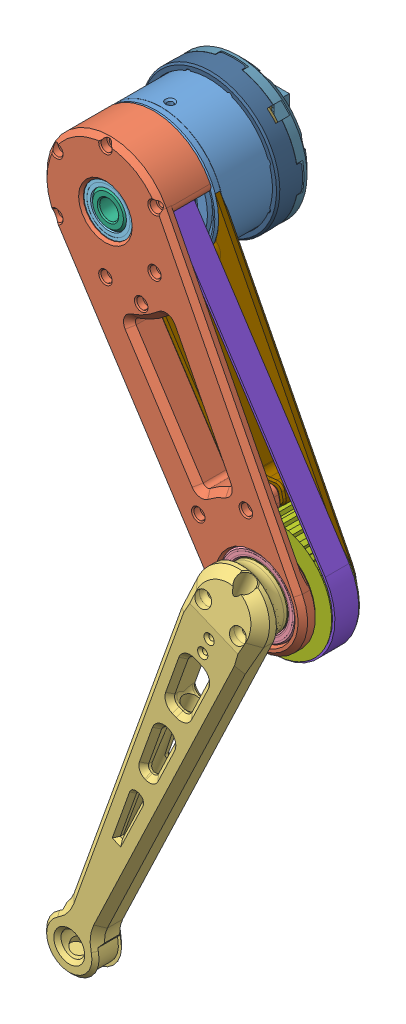
SolidWorks assembly Leg 010, configuration Default. Lengths in mm.
Overall size (133.1 311.2 88.94).
16 component instances, 15 part files, 37 mates.
Components (placement in the parent):
- Servo 010-1: Servo 010 [Default] at (15.0435 28.5731 29.2983) size (52.8 52.8 26)
- Femur 011-1: Femur 011 [Default] at (15.0435 28.5731 74.4483) x (0.866025 0.5 0) z (0 0 1) size (53 172 20.25)
- Low Limb 020-1: Low Limb 020 [Predeterminado] at (77.7935 -80.1131 89.8983) x (-0.92322 0.384271 0) z (0 0 -1) size (30 188.77 21.4)
- 6705 Bearing-1: 6705 Bearing [Predeterminado] at (77.7935 -80.1131 71.4983) x (0.989844 0.142156 0) z (0.142156 -0.989844 0) size (32 4.1 32)
- Bearing 15x24x5mm-1: Bearing 15x24x5mm [Predeterminado] at (15.0435 28.5731 70.6483) x (1 0 0) z (0 -1 0) size (24 5.1 24)
- Pulley A 36T 011-1: Pulley A 36T 011 [Predeterminado] at (15.0435 28.5731 66.0983) x (-0.95639 -0.292092 0) z (0 0 -1) size (36.31 36.31 18.05)
- Pulley B 36T 010-2: Pulley B 36T 010 [Predeterminado] at (77.7935 -80.1131 55.8983) x (0.384271 0.92322 0) z (0 0 1) size (49.11 49.11 20.55)
- Belt 380mm 010-1: Belt 380mm 010 [Default] at (77.7935 -80.1131 65.9983) x (-0.5 0.866025 0) z (-0.866025 -0.5 0) size (168.7 10 50)
- Femur B 011-1: Femur B 011 [Default] at (15.0435 28.5731 49.7229) x (-0.866025 -0.5 0) z (0 0 -1) size (52.55 140.48 13)
- 6705 Bearing-2: 6705 Bearing [Predeterminado] at (77.7935 -80.1131 52.4229) x (0.58942 -0.807827 0) z (-0.807827 -0.58942 0) size (32 4.1 32)
- Back Plate 011-1: Back Plate 011 [Default] at (15.0435 28.5731 31.0483) x (1 0 0) z (0 1 0) size (58 10.25 57.37)
- Pulley B Plate 010-1: Pulley B Plate 010 [Default] at (77.7935 -80.1131 48.8983) x (-0.384271 -0.92322 0) z (0 0 -1) size (27 27 7.25)
- Dagor Controller Board 2.5-1: Dagor Controller Board 2.5 [Predeterminado] at (15.0435 28.5731 24.4983) size (44 44 7.5)
- ESP32-WROOM-32U-1: ESP32-WROOM-32U [Default] at (9.0435 43.9731 23.5333) x (1 0 0) z (0 0 -1) size (18.07 19.38 3.04)
- Back Plate B 011-1: Back Plate B 011 [Default] at (15.0435 28.5731 22.7073) x (-1 0 0) z (0 0 -1) size (58 58 21.75)
- Magnet Holder 010-1: Magnet Holder 010 [Default] at (15.0435 28.5731 36.0983) x (1 0 0) z (0 0 -1) size (9 9 8.5)
Mates (geometry in assembly coordinates):
- Concentric1: concentric anti-aligned: cylinder of Servo 010-1 through (15.0435 28.5731 54.1983) axis (0 0 -1) radius 26.4; cylinder of Femur 011-1 through (15.0435 28.5731 70.4483) axis (0 0 1) radius 26.5
- Coincident1: coincident anti-aligned: plane of Servo 010-1 through (15.0435 28.5731 54.1983) normal (0 0 1); plane of Femur 011-1 through (15.0435 28.5731 54.1983) normal (0 0 -1)
- Concentric2: concentric aligned: cylinder of Servo 010-1 through (35.6116 40.4481 49.0983) axis (0 0 1) radius 1.25; cylinder of Femur 011-1 through (35.6116 40.4481 70.4483) axis (0 0 1) radius 1.4
- Concentric3: concentric aligned: cylinder of Femur 011-1 through (77.7935 -80.1131 70.4483) axis (0 0 1) radius 14.25; cylinder of Low Limb 020-1 through (77.7935 -80.1131 73.4983) axis (0 0 1) radius 12.5
- Coincident3: coincident anti-aligned: plane of Low Limb 020-1 through (77.7935 -80.1131 73.4983) normal (0 0 -1); plane of 6705 Bearing-1 through (77.7935 -80.1131 73.4983) normal (0 0 1)
- Concentric5: concentric aligned: cylinder of Femur 011-1 through (15.0435 28.5731 73.1983) axis (0 0 -1) radius 12.2; cylinder of Bearing 15x24x5mm-1 through (15.0435 28.5731 73.1483) axis (0 0 -1) radius 12
- Coincident4: coincident anti-aligned: plane of Femur 011-1 through (15.0435 28.5731 73.1983) normal (0 0 -1); plane of Bearing 15x24x5mm-1 through (15.0435 28.5731 73.1983) normal (0 0 1)
- Concentric7: concentric aligned: cylinder of 6705 Bearing-1 through (77.7935 -80.1131 73.4983) axis (0 0 -1) radius 12.5; cylinder of Pulley B 36T 010-2 through (77.7935 -80.1131 72.1983) axis (0 0 -1) radius 12.45
- Concentric8: concentric aligned: cylinder of Bearing 15x24x5mm-1 through (15.0435 28.5731 73.1483) axis (0 0 -1) radius 7.5; cylinder of Pulley A 36T 010-1 through (15.0435 28.5731 73.3483) axis (0 0 -1) radius 7.45
- Coincident7: coincident anti-aligned: plane of Servo 010-1 through (15.0435 28.5731 55.2983) normal (0 0 1); plane of Pulley A 36T 010-1 through (15.0435 28.5731 55.2983) normal (0 0 -1)
- Parallel1: parallel anti-aligned: plane of Low Limb 020-1 through (85.4795 -73.6179 68.4983) normal (0.92322 -0.384271 0); plane of Pulley B 36T 010-2 through (85.5449 -73.5909 63.1983) normal (-0.92322 0.384271 0)
- Concentric9: concentric aligned: cylinder of Pulley A 36T 010-1 through (15.0435 28.5731 55.8983) axis (0 0 1) radius 17.4; cylinder of Belt 380mm 010-1 through (15.0435 28.5731 55.9983) axis (0 0 1) radius 17.2
- Concentric10: concentric anti-aligned: cylinder of Pulley B 36T 010-2 through (77.7935 -80.1131 66.0983) axis (0 0 -1) radius 24; cylinder of Belt 380mm 010-1 through (77.7935 -80.1131 55.9983) axis (0 0 1) radius 24
- Width1: width anti-aligned: plane of Pulley A 36T 011-1 through (15.0435 28.5731 66.0983) normal (0 0 -1); plane of Belt 380mm 010-1 through (15.0435 28.5731 55.8983) normal (0 0 1); plane of Pulley A 36T 011-1 through (77.7935 -80.1131 65.9983) normal (0 0 1); plane of Belt 380mm 010-1 through (77.7935 -80.1131 55.9983) normal (0 0 -1)
- Concentric14: concentric anti-aligned: cylinder of Servo 010-1 through (15.0435 28.5731 54.1983) axis (0 0 -1) radius 26.4; cylinder of Femur B 010-1 through (15.0435 28.5731 43.7229) axis (0 0 1) radius 26.75
- Concentric15: concentric aligned: cylinder of Femur B 010-1 through (77.7935 -80.1131 54.4729) axis (0 0 -1) radius 16.25; cylinder of 6705 Bearing-2 through (77.7935 -80.1131 54.4229) axis (0 0 -1) radius 16
- Coincident10: coincident anti-aligned: plane of Femur B 010-1 through (77.7935 -80.1131 54.4729) normal (0 0 -1); plane of 6705 Bearing-2 through (77.7935 -80.1131 54.4729) normal (0 0 1)
- Concentric16: concentric anti-aligned: cylinder of Pulley B 36T 010-2 through (77.7935 -80.1131 51.6483) axis (0 0 1) radius 12.45; cylinder of 6705 Bearing-2 through (77.7935 -80.1131 54.4229) axis (0 0 -1) radius 12.5
- Concentric17: concentric anti-aligned: cylinder of Femur 011-1 through (77.7935 -80.1131 69.4483) axis (0 0 1) radius 16.25; cylinder of 6705 Bearing-1 through (77.7935 -80.1131 73.4983) axis (0 0 -1) radius 16
- Coincident11: coincident anti-aligned: plane of Femur 011-1 through (77.7935 -80.1131 69.4483) normal (0 0 1); plane of 6705 Bearing-1 through (77.7935 -80.1131 69.4483) normal (0 0 -1)
- Width2: width anti-aligned: plane of Belt 380mm 010-1 through (77.7935 -80.1131 65.9983) normal (0 0 1); plane of Pulley B 36T 010-2 through (77.7935 -80.1131 55.9983) normal (0 0 -1); plane of Belt 380mm 010-1 through (77.7935 -80.1131 66.0983) normal (0 0 -1); plane of Pulley B 36T 010-2 through (77.7935 -80.1131 55.8983) normal (0 0 1)
- Concentric18: concentric anti-aligned: cylinder of Servo 010-1 through (15.0435 28.5731 31.3983) axis (0 0 -1) radius 9; cylinder of Back Plate 010-1 through (15.0435 28.5731 29.2983) axis (0 0 1) radius 8.75
- Concentric19: concentric anti-aligned: cylinder of Servo 010-1 through (9.0435 28.5731 33.5983) axis (0 0 -1) radius 1.25; cylinder of Back Plate 010-1 through (9.0435 28.5731 29.2983) axis (0 0 1) radius 1.25
- Coincident13: coincident anti-aligned: plane of Pulley B 36T 010-2 through (77.7935 -80.1131 51.6483) normal (0 0 -1); plane of Pulley B Plate 010-1 through (77.7935 -80.1131 51.6483) normal (0 0 1)
- Concentric20: concentric aligned: cylinder of 6705 Bearing-2 through (77.7935 -80.1131 54.4229) axis (0 0 -1) radius 12.5; cylinder of Pulley B Plate 010-1 through (77.7935 -80.1131 51.6483) axis (0 0 -1) radius 12.45
- Concentric21: concentric aligned: cylinder of Pulley B 36T 010-2 through (74.9641 -86.9107 56.6483) axis (0 0 -1) radius 1.45; cylinder of Pulley B Plate 010-1 through (74.9641 -86.9107 51.6483) axis (0 0 -1) radius 1.7
- Coincident14: coincident anti-aligned: plane of Back Plate 010-1 through (15.0435 28.5731 25.2983) normal (0 0 -1); plane of Dagor Controller Board 2.5-1 through (2.5345 41.0821 25.2983) normal (0 0 1)
- Coincident15: coincident anti-aligned: plane of Servo 010-1 through (15.0435 28.5731 29.2983) normal (0 0 -1); plane of Back Plate 010-1 through (15.0435 28.5731 29.2983) normal (0 0 1)
- Concentric23: concentric aligned: cylinder of Back Plate 010-1 through (-3.9565 46.0731 22.7983) axis (0 0 1) radius 1.2; cylinder of Dagor Controller Board 2.5-1 through (-3.9565 46.0731 23.6983) axis (0 0 1) radius 1.5
- Concentric24: concentric aligned: cylinder of Back Plate 010-1 through (34.0435 11.0731 22.7983) axis (0 0 1) radius 1.2; cylinder of Dagor Controller Board 2.5-1 through (34.0435 11.0731 23.6983) axis (0 0 1) radius 1.5
- Coincident16: coincident anti-aligned: plane of Dagor Controller Board 2.5-1 through (15.0435 28.5731 23.4983) normal (0 0 -1); plane of ESP32-WROOM-32U-1 through (18.0435 31.2231 23.4983) normal (0 0 1)
- Width3: width aligned: plane of Dagor Controller Board 2.5-1 through (0.0435 50.5731 23.4983) normal (-1 0 0); plane of ESP32-WROOM-32U-1 through (18.0435 50.5731 23.4983) normal (1 0 0); plane of Dagor Controller Board 2.5-1 through (0.0435 49.4731 23.4983) normal (-1 0 0); plane of ESP32-WROOM-32U-1 through (18.0435 56.7231 23.4983) normal (1 0 0)
- Coincident17: coincident aligned: plane of Dagor Controller Board 2.5-1 through (18.0435 31.2231 23.4983) normal (0 -1 0); plane of ESP32-WROOM-32U-1 through (18.0435 31.2231 23.4983) normal (0 -1 0)
- Concentric25: concentric anti-aligned: cylinder of Servo 010-1 through (15.0435 28.5731 54.1983) axis (0 0 -1) radius 26.4; cylinder of Back Plate B 010-1 through (15.0435 28.5731 15.9573) axis (0 0 1) radius 29
- Parallel2: parallel anti-aligned: plane of Back Plate 010-1 through (37.2935 34.0731 20.7983) normal (0 1 0); plane of Back Plate B 010-1 through (37.0441 34.3231 20.2073) normal (0 -1 0)
- Concentric26: concentric anti-aligned: cylinder of Servo 010-1 through (15.0435 28.5731 35.6983) axis (0 0 -1) radius 2.9; cylinder of Magnet Holder 010-1 through (15.0435 28.5731 33.0983) axis (0 0 1) radius 2.95
- Coincident19: coincident anti-aligned: plane of Servo 010-1 through (15.0435 28.5731 33.5983) normal (0 0 -1); plane of Magnet Holder 010-1 through (15.0435 28.5731 33.5983) normal (0 0 1)
